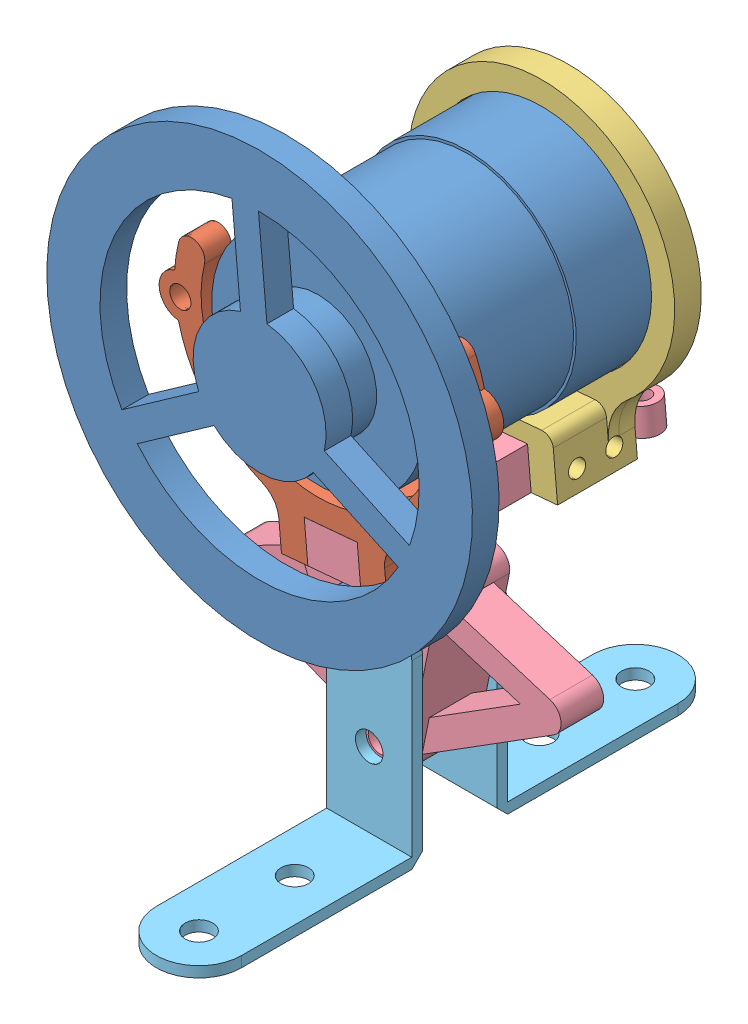
SolidWorks assembly flywheel_test, configuration 默认. Lengths in mm.
Overall size (86.9 121.22 98).
6 component instances, 5 part files, 14 mates.
Components (placement in the parent):
- flywheel-1: flywheel [默认] at (-42.9655 77.7668 57.1264) x (0.995913 0.090314 0) z (0 0 1) size (80 80 59)
- flywheel_holder1-1: flywheel_holder1 [默认] at (-42.9655 77.7668 105.1264) x (0.995913 0.090314 0) z (-0.090314 0.995913 0) size (60 15 44.31)
- flywheel_holder2-1: flywheel_holder2 [默认] at (-42.9655 77.7668 58.1264) x (-0.995913 -0.090314 0) z (-0.090314 0.995913 0) size (50 15 58.81)
- flywheel_test_frame-1: flywheel_test_frame [默认] at (-40.2561 47.8894 81.6264) x (0.995913 0.090314 0) z (0 0 1) size (64.93 41.13 53.5)
- hinge-1: hinge [默认] at (-37.3642 2 101.1264) x (-1 0 0) z (0 0 -1) size (16 42 42)
- hinge-2: hinge [默认] at (-37.3642 2 83.1264) size (16 42 42)
Mates (geometry in assembly coordinates):
- 同心1: concentric anti-aligned: cylinder of flywheel-1 through (-42.9655 77.7668 105.1264) axis (0 0 -1) radius 20; cylinder of flywheel_holder1-1 through (-42.9655 77.7668 100.1264) axis (0 0 1) radius 22
- 同心2: concentric aligned: cylinder of flywheel-1 through (-42.9655 77.7668 77.1264) axis (0 0 -1) radius 20.5; cylinder of flywheel_holder2-1 through (-42.9655 77.7668 63.1264) axis (0 0 -1) radius 20.65
- 距离1: distance = 1 mm aligned: plane of flywheel_holder2-1 through (-42.9655 77.7668 58.1264) normal (0 0 -1); plane of flywheel-1 through (-42.9655 77.7668 57.1264) normal (0 0 -1)
- 距离2: distance = 0 mm aligned: plane of flywheel_holder1-1 through (-54.858 80.7048 105.1264) normal (0 0 1); plane of flywheel-1 through (-42.9655 77.7668 105.1264) normal (0 0 1)
- 平行2: parallel aligned: plane of flywheel_holder1-1 through (-42.9655 77.7668 105.1264) normal (-0.090314 0.995913 0); plane of flywheel_holder2-1 through (-42.9655 77.7668 58.1264) normal (-0.090314 0.995913 0)
- 重合9: coincident aligned: circle of flywheel_holder1-1; circle of flywheel_test_frame-1
- 重合10: coincident aligned: circle of flywheel_holder1-1; circle of flywheel_test_frame-1
- 重合14: coincident anti-aligned: plane of hinge-1 through (-37.3642 0 133.1264) normal (0 -1 0)
- 重合15: coincident anti-aligned: plane of hinge-2 through (-37.3642 0 51.1264) normal (0 -1 0)
- 重合17: coincident aligned: plane of flywheel-1 through (-42.9655 77.7668 57.1264) normal (-0.090314 0.995913 0); plane of flywheel_holder1-1 through (-42.9655 77.7668 105.1264) normal (-0.090314 0.995913 0)
- 同心4: concentric anti-aligned: circle of flywheel_test_frame-1; circle of hinge-1
- 重合18: coincident anti-aligned: plane of flywheel_test_frame-1 through (-40.2561 47.8894 99.1264) normal (0 0 1); plane of hinge-1 through (-37.3642 34 99.1264) normal (0 0 -1)
- 同心5: concentric aligned: circle of flywheel_test_frame-1; circle of hinge-2
- 重合19: coincident anti-aligned: plane of flywheel_test_frame-1 through (-40.2561 47.8894 85.1264) normal (0 0 -1); plane of hinge-2 through (-37.3642 34 85.1264) normal (0 0 1)
